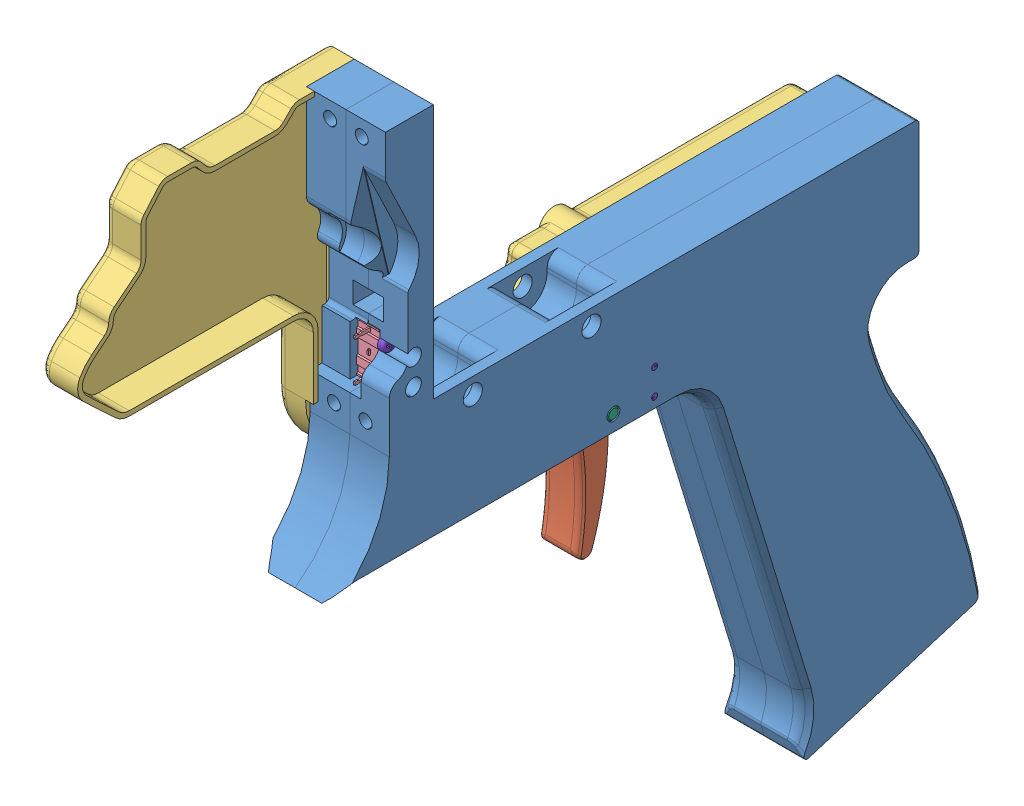
SolidWorks assembly Handle, configuration Default. Lengths in mm.
Overall size (27 190.53 211.73).
15 component instances, 9 part files, 0 mates.
Components (placement in the parent):
- Handle-1: Handle [Default] at origin size (20 190.53 164.74)
- Trigger-1: Trigger [Default] at origin size (10.47 40.44 9.72)
- Wire Cover-1: Wire Cover [Default] at origin size (9 94.67 192.47)
- OMRON_D2F_Switch-1: OMRON_D2F_Switch [Default] at (-0.1 -41.92 -73.1371) x (-1 0 0) z (0 0 1) size (5.8 12.7 10.48)
- OMRON_D2F_Switch-2: OMRON_D2F_Switch [Default] at (0 -9.32 -15.9812) x (1 0 0) z (0 0 -1) size (5.8 12.7 10.48)
- spring^thumbscrew-1: spring^thumbscrew [Default] at (-2 -41.6576 -47.6371) x (-1 0 0) z (0 0 1) size (6.3 6.21 13.06)
- Dowel Pin 3mm(20mm)-1: Dowel Pin 3mm(20mm) [Default] at (0 -43.77 -64.6371) x (0 0 -1) z (-1 0 0) size (3 3 20)
- socket head cap screw_am(B18.3.1M - 3 x 0.5 x 8 Hex SHCS -- 8NHX)-1: socket head cap screw_am(B18.3.1M - 3 x 0.5 x 8 Hex SHCS -- 8NHX) [Default] at (-17 -33.77 -135.6371) size (11 5.5 5.5)
- socket head cap screw_am(B18.3.1M - 3 x 0.5 x 8 Hex SHCS -- 8NHX)-2: socket head cap screw_am(B18.3.1M - 3 x 0.5 x 8 Hex SHCS -- 8NHX) [Default] at (-17 -21.77 -76.6371) size (11 5.5 5.5)
- pan head tapping screw_am(PHT 2x13x12.2-type I-D-N)-1: pan head tapping screw_am(PHT 2x13x12.2-type I-D-N) [Default] at (-4.4 -38.67 -75.0371) x (1 0 0) z (0 0 -1) size (14.4 4 4)
- pan head tapping screw_am(PHT 2x13x12.2-type I-D-N)-2: pan head tapping screw_am(PHT 2x13x12.2-type I-D-N) [Default] at (4.3 -6.07 -14.0813) x (-1 0 0) z (0 0 1) size (14.4 4 4)
- pan head tapping screw_am(PHT 2x13x12.2-type I-D-N)-3: pan head tapping screw_am(PHT 2x13x12.2-type I-D-N) [Default] at (-4.4 -45.17 -75.0371) size (14.4 4 4)
- pan head tapping screw_am(PHT 2x13x12.2-type I-D-N)-4: pan head tapping screw_am(PHT 2x13x12.2-type I-D-N) [Default] at (4.3 -12.57 -14.0813) x (-1 0 0) z (0 0 1) size (14.4 4 4)
- 94180A331_HEAT-SET INSERTS FOR PLASTICS-1: 94180A331_HEAT-SET INSERTS FOR PLASTICS [Default] at (-10 -33.77 -135.6371) x (0 0 1) z (0 -1 0) size (5.56 4.12 5.56)
- 94180A331_HEAT-SET INSERTS FOR PLASTICS-2: 94180A331_HEAT-SET INSERTS FOR PLASTICS [Default] at (-10 -21.77 -76.6371) x (0 0 1) z (0 -1 0) size (5.56 4.12 5.56)
